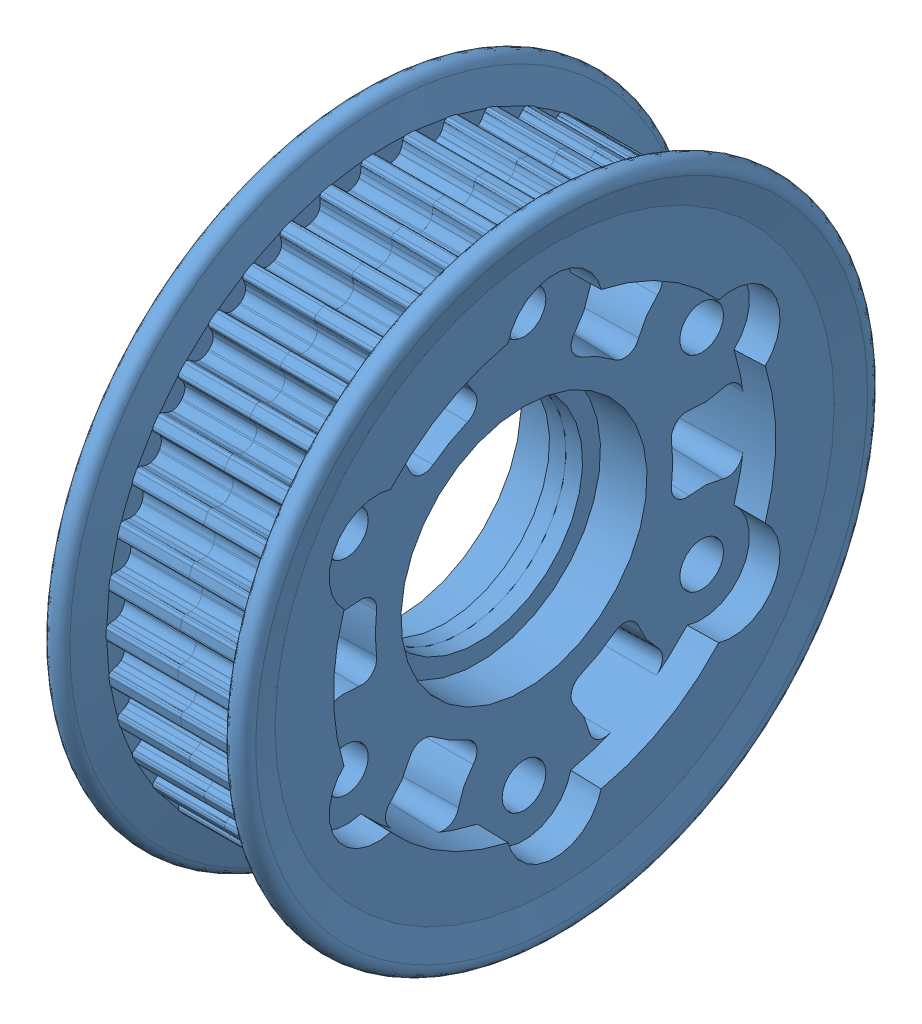
SolidWorks assembly 42 - 2014 tooth pulley assembly, configuration Default. Lengths in mm.
Overall size (23.46 74.23 74.23).
2 component instances, 1 part files, 0 mates.
Components (placement in the parent):
- 42 tooth HTD Pulley half 2014-1: 42 tooth HTD Pulley half 2014 [Default] at origin size (13 74.23 74.23)
- 42 tooth HTD Pulley half 2014-2: 42 tooth HTD Pulley half 2014 [Default] at (16.6624 0 0) x (-1 0 0) z (0 0.000084 1) size (13 74.23 74.23)
